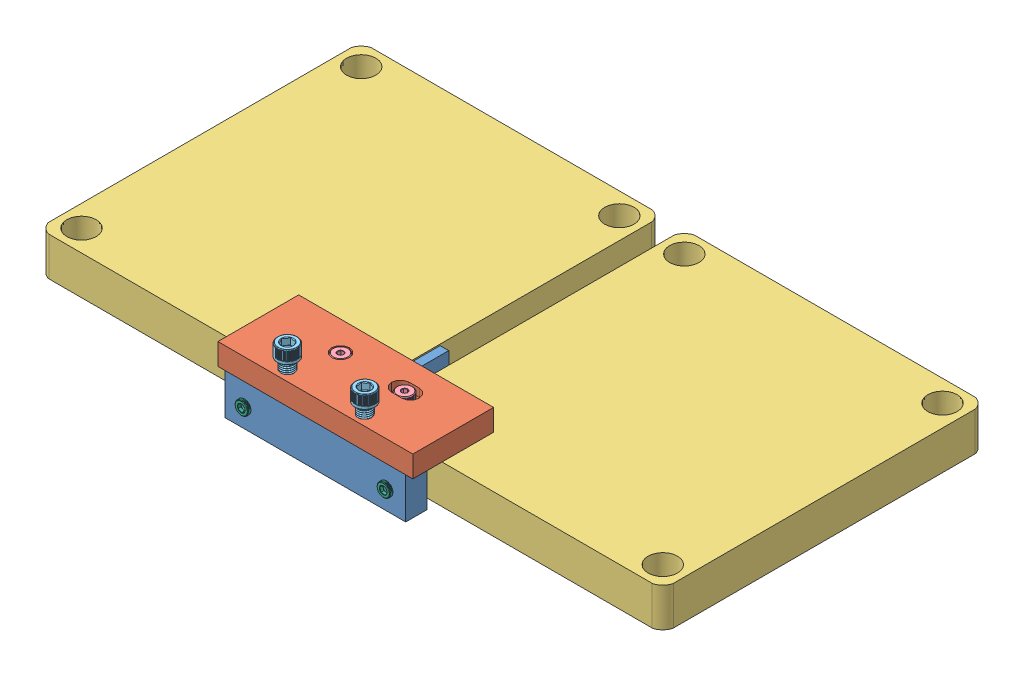
SolidWorks assembly Set up fixture assembly, configuration Default. Lengths in mm.
Overall size (368.61 67.03 209.85).
11 component instances, 7 part files, 22 mates.
Components (placement in the parent):
- Part1-2: Part1 [Default] at (159.6792 150.4313 94.1635) size (106.68 24.13 76.2)
- Part 2-2: Part 2 [Default] at (159.6722 174.5613 94.1635) x (1 0 0) z (0 1 0) size (115.06 47.69 12.7)
- Main set up part(Clark Edit)-2: Main set up part(Clark Edit) [Default] at (67.8582 152.1262 -18.3585) x (-1 0 0) z (0 1 0) size (177.86 190.56 22.92)
- Main set up part(Clark Edit)-4: Main set up part(Clark Edit) [Default] at (258.6052 151.7013 -18.3585) x (1 0 0) z (0 1 0) size (177.86 190.56 22.92)
- 91259A546_Alloy Steel Shoulder Screw (1)-1: 91259A546_Alloy Steel Shoulder Screw (1) [91259A546] at (144.0512 161.0548 63.6835) x (0.916063 0 0.401033) z (0 1 0) size (9.53 9.53 52.91)
- 91259A546_Alloy Steel Shoulder Screw (1)-2: 91259A546_Alloy Steel Shoulder Screw (1) [91259A546] at (182.4052 161.0548 64.1915) x (1 0 0) z (0 1 0) size (9.53 9.53 52.91)
- 90128A757_Zinc-Plated Alloy Steel Socket Head Screw-1: 90128A757_Zinc-Plated Alloy Steel Socket Head Screw [90128A757] at (136.8192 178.1759 87.8135) x (-0.821589 0 -0.570081) z (0 1 0) size (11.93 11.93 47.03)
- 90128A757_Zinc-Plated Alloy Steel Socket Head Screw-2: 90128A757_Zinc-Plated Alloy Steel Socket Head Screw [90128A757] at (182.5392 178.1759 87.8135) x (0.355447 0 -0.934697) z (0 1 0) size (11.93 11.93 47.03)
- 92196A243_18-8 Stainless Steel Socket Head Screw-1: 92196A243_18-8 Stainless Steel Socket Head Screw [92196A243] at (117.7692 161.8613 86.4482) x (0.999551 0.02996 0) z (0 0 1) size (7.93 7.93 19.7)
- 92196A243_18-8 Stainless Steel Socket Head Screw-2: 92196A243_18-8 Stainless Steel Socket Head Screw [92196A243] at (201.5892 161.8613 86.4482) x (-0.784107 0.620626 0) z (0 0 1) size (7.93 7.93 19.7)
- 92314A239_18-8 Stainless Steel Hex Head Screws (1)-1: 92314A239_18-8 Stainless Steel Hex Head Screws (1) [92314A239] at (163.1082 163.1313 38.2835) x (-1 0 0) z (0 0 -1) size (9.87 9.09 7.94)
Mates (geometry in assembly coordinates):
- Coincident2: coincident anti-aligned: plane of Part1-2 through (159.6792 174.5613 94.1635) normal (0 1 0); plane of Part 2-2 through (159.6722 174.5613 94.1635) normal (0 -1 0)
- Parallel5: parallel aligned: plane of Main set up part(Clark Edit)-2 through (67.8582 152.1262 -18.3585) normal (0 -1 0); plane of Main set up part(Clark Edit)-4 through (258.6052 151.7013 -18.3585) normal (0 -1 0)
- Coincident15: coincident anti-aligned: plane of Part 2-2 through (159.6722 174.5613 94.1635) normal (0 -1 0); plane of Main set up part(Clark Edit)-4 through (258.6052 174.5613 -18.3585) normal (0 1 0)
- Lock1: lock: unknown of Main set up part(Clark Edit)-2; unknown of Main set up part(Clark Edit)-4
- Coincident17: coincident aligned: plane of Part1-2 through (213.0192 174.5613 94.1635) normal (0 0 1); plane of Part 2-2 through (102.1412 187.2613 94.1635) normal (0 0 1)
- Distance1: distance = 0.381 mm: line of Part1-2 through (157.1392 150.4313 17.9635) axis (0 0 1); plane of Main set up part(Clark Edit)-2 through (156.7582 174.9862 76.8915) normal (1 0 0)
- Concentric1: concentric aligned: circle of Part 2-2; circle of 91259A546_Alloy Steel Shoulder Screw (1)-1
- Coincident19: coincident anti-aligned: plane of Part 2-2 through (149.21 182.4861 63.6835) normal (0 1 0); plane of 91259A546_Alloy Steel Shoulder Screw (1)-1 through (145.9612 182.4861 59.3207) normal (0 -1 0)
- Coincident23: coincident aligned: plane of 91259A546_Alloy Steel Shoulder Screw (1)-1 through (145.7702 187.2486 59.757) normal (0 1 0); plane of 91259A546_Alloy Steel Shoulder Screw (1)-2 through (182.4052 187.2486 59.9052) normal (0 1 0)
- Coincident24: coincident anti-aligned: plane of Part 2-2 through (188.7552 182.4861 63.6835) normal (0 1 0); plane of 91259A546_Alloy Steel Shoulder Screw (1)-2 through (182.4052 182.4861 59.429) normal (0 -1 0)
- Concentric2: concentric aligned: circle of Main set up part(Clark Edit)-4; circle of 91259A546_Alloy Steel Shoulder Screw (1)-2
- Coincident25: coincident anti-aligned: cone of Part1-2 through (136.8192 155.2573 87.8135) axis (0 -1 0); circle of 90128A757_Zinc-Plated Alloy Steel Socket Head Screw-1
- Coincident27: coincident anti-aligned: cone of Part1-2 through (182.5392 155.2573 87.8135) axis (0 -1 0); circle of 90128A757_Zinc-Plated Alloy Steel Socket Head Screw-2
- Coincident28: coincident aligned: plane of 90128A757_Zinc-Plated Alloy Steel Socket Head Screw-1 through (133.7461 201.1946 92.2423) normal (0 1 0); plane of 90128A757_Zinc-Plated Alloy Steel Socket Head Screw-2 through (177.5007 201.1946 85.8974) normal (0 1 0)
- Coincident29: coincident anti-aligned: plane of Main set up part(Clark Edit)-2 through (156.7582 174.9862 76.8915) normal (0 0 1); circle of 92196A243_18-8 Stainless Steel Socket Head Screw-1
- Concentric3: concentric anti-aligned: circle of Part1-2; circle of 92196A243_18-8 Stainless Steel Socket Head Screw-1
- Concentric4: concentric anti-aligned: circle of Part1-2; circle of 92196A243_18-8 Stainless Steel Socket Head Screw-2
- Coincident30: coincident anti-aligned: plane of Main set up part(Clark Edit)-4 through (169.7052 174.5613 76.8915) normal (0 0 1); circle of 92196A243_18-8 Stainless Steel Socket Head Screw-2
- Lock2: lock: unknown of 92196A243_18-8 Stainless Steel Socket Head Screw-1; unknown of 92196A243_18-8 Stainless Steel Socket Head Screw-2
- Lock3: lock: unknown of 90128A757_Zinc-Plated Alloy Steel Socket Head Screw-1; unknown of 90128A757_Zinc-Plated Alloy Steel Socket Head Screw-2
- Concentric5: concentric anti-aligned: circle of Part1-2; cone of 92314A239_18-8 Stainless Steel Hex Head Screws (1)-1 through (156.7582 163.1313 38.2835) axis (-1 0 0)
- Lock4: lock: unknown of Part1-2; unknown of 92314A239_18-8 Stainless Steel Hex Head Screws (1)-1
